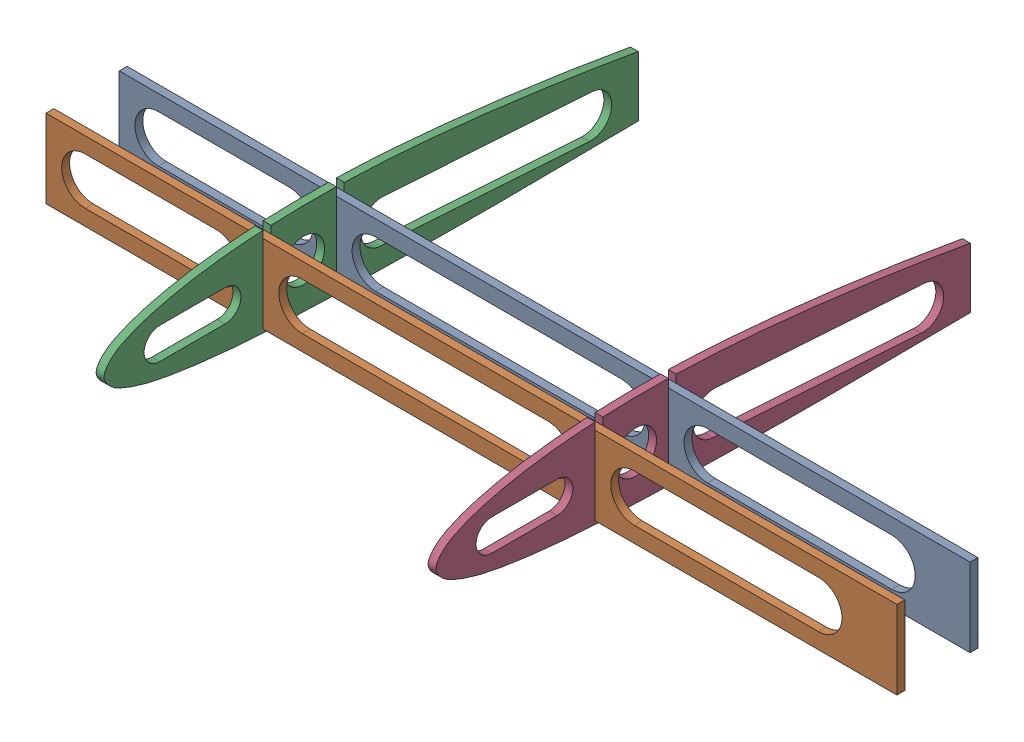
SolidWorks assembly innerWing_structure_L, configuration Default. Lengths in mm.
Overall size (325.28 36.52 204.27).
4 component instances, 2 part files, 10 mates.
Components (placement in the parent):
- stringer_inner-1: stringer_inner [Default] at (-174.2927 10.0448 -3) x (1 0 0) z (0 -1 0) size (325.28 3 30)
- stringer_inner-2: stringer_inner [Default] at (-174.2927 10.0448 25) x (1 0 0) z (0 -1 0) size (325.28 3 30)
- wingStructure_innerRib-1: wingStructure_innerRib [Default] at (-444.7927 3.2039 89.3108) x (0 0 -1) z (1 0 0) size (204.27 36.52 3.02)
- wingStructure_innerRib-2: wingStructure_innerRib [Default] at (-317.8927 3.2039 89.3108) x (0 0 -1) z (1 0 0) size (204.27 36.52 3.02)
Mates (geometry in assembly coordinates):
- Coincident1: coincident aligned: plane of stringer_inner-1 through (-174.2927 10.0448 0) normal (0 0 1)
- Coincident22: coincident anti-aligned: plane of stringer_inner-2 through (-174.2927 10.0448 28) normal (0 0 1); plane of fuseStructure_innerRib-2 through (22.6844 10.0448 28) normal (0 0 -1)
- Coincident23: coincident anti-aligned: plane of stringer_inner-2 through (35.6073 -4.9552 25) normal (-1 0 0); plane of fuseStructure_innerRib-2 through (35.6073 12.8943 87.3801) normal (1 0 0)
- Coincident24: coincident anti-aligned: plane of stringer_inner-2 through (32.6073 10.0448 25) normal (0 -1 0); plane of fuseStructure_innerRib-2 through (22.6844 10.0448 28) normal (0 1 0)
- Coincident25: coincident anti-aligned: plane of stringer_inner-2 through (-174.2927 10.0448 28) normal (0 0 1); plane of fuseStructure_innerRib-1 through (-104.2156 10.0448 28) normal (0 0 -1)
- Coincident26: coincident anti-aligned: plane of stringer_inner-2 through (-91.2927 -4.9552 25) normal (-1 0 0); plane of fuseStructure_innerRib-1 through (-91.2927 12.8943 87.3801) normal (1 0 0)
- Coincident27: coincident anti-aligned: plane of stringer_inner-2 through (-94.2927 10.0448 25) normal (0 -1 0); plane of fuseStructure_innerRib-1 through (-104.2156 10.0448 28) normal (0 1 0)
- Coincident28: coincident anti-aligned: plane of stringer_inner-1 through (-174.2927 10.0448 0) normal (0 0 1); plane of fuseStructure_innerRib-1 through (-104.2156 10.0448 0) normal (0 0 -1)
- Coincident29: coincident anti-aligned: plane of stringer_inner-1 through (-94.2927 -4.9552 -3) normal (1 0 0); plane of fuseStructure_innerRib-1 through (-94.2927 12.8943 87.3801) normal (-1 0 0)
- Coincident30: coincident anti-aligned: plane of stringer_inner-1 through (-94.2927 10.0448 -3) normal (0 -1 0); plane of fuseStructure_innerRib-1 through (-104.2156 10.0448 0) normal (0 1 0)
